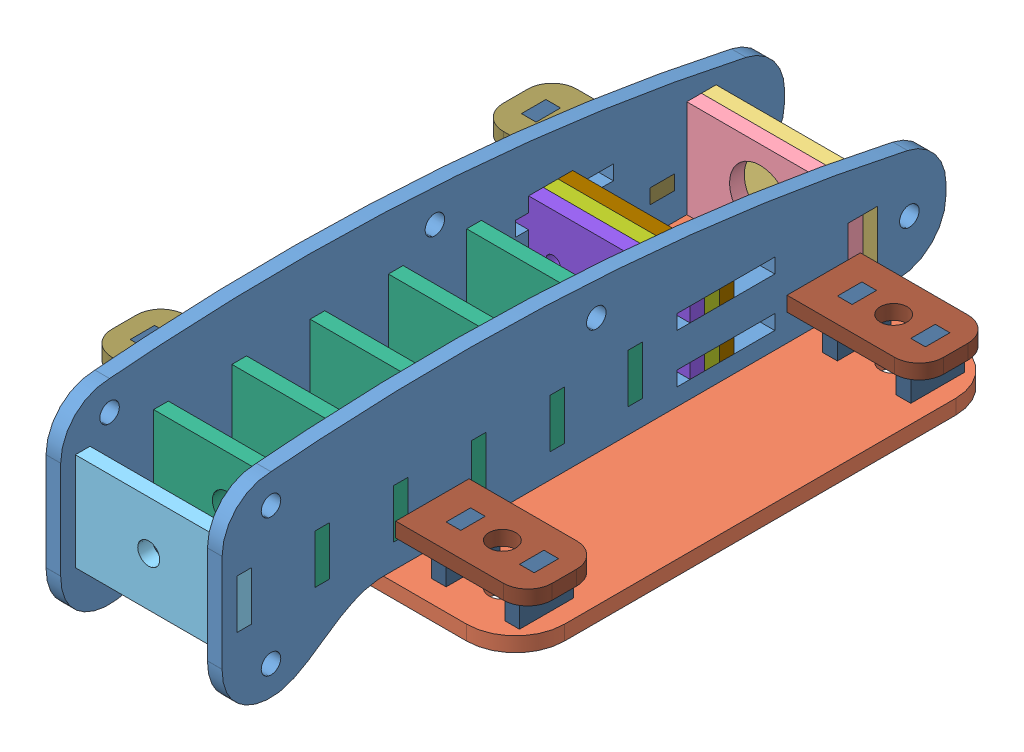
SolidWorks assembly holder_assembly, configuration Default. Lengths in mm.
Overall size (90 45.93 148.02).
26 component instances, 12 part files, 75 mates.
Components (placement in the parent):
- slider_holder-1: slider_holder [Default] at (-5.6502 23.4404 8.9705) x (0 -1 0) z (0 0 1) size (45.93 3 148.02)
- slider_holder-2: slider_holder [Default] at (-38.6502 23.4404 8.9705) x (0 -1 0) z (0 0 1) size (45.93 3 148.02)
- baseplate-1: baseplate [Default] at (-20.6502 20.4404 -26.0295) size (90 3 100)
- top_springstop-2: top_springstop [Default] at (-20.6502 33.4404 -77.0295) x (1 0 0) z (0 -1 0) size (36 3 20)
- top_big_springstop-2: top_big_springstop [Default] at (-20.6502 33.4404 -71.0295) x (-1 0 0) z (0 -1 0) size (36 3 20)
- bottom_stop-2: bottom_stop [Default] at (-20.6502 33.4404 50.9705) x (1 0 0) z (0 -1 0) size (36 3 20)
- pen_bodyholder-1: pen_bodyholder [Default] at (-20.6502 33.4404 -13.0295) x (1 0 0) z (0 -1 0) size (36 3 20)
- pen_bodyholder-2: pen_bodyholder [Default] at (-20.6502 33.4404 2.9705) x (1 0 0) z (0 -1 0) size (36 3 20)
- pen_bodyholder-4: pen_bodyholder [Default] at (-20.6502 33.4404 -29.0295) x (1 0 0) z (0 -1 0) size (36 3 20)
- pen_bodyholder-5: pen_bodyholder [Default] at (-20.6502 33.4404 34.9705) x (1 0 0) z (0 -1 0) size (36 3 20)
- pen_bodyholder-6: pen_bodyholder [Default] at (-20.6502 33.4404 18.9705) x (1 0 0) z (0 -1 0) size (36 3 20)
- spring_slider-1: spring_slider [Default] at (4.2172 29.9404 -44.6987) x (1 0 0) z (0 -1 0) size (36 3 19)
- spring_slider_pen-1: spring_slider_pen [Default] at (4.2172 36.9404 -38.6987) x (1 0 0) z (0 1 0) size (36 3 19)
- spring_slider_spring-1: spring_slider_spring [Default] at (4.2172 29.9404 -47.6987) x (1 0 0) z (0 -1 0) size (36 3 19)
- brace-1: brace [Default] at (-58.9502 36.6605 -67.8741) x (0 1 0) z (0 0 1) size (11.5 3 11)
- brace-2: brace [Default] at (-58.9502 36.6605 12.1259) x (0 1 0) z (0 0 1) size (11.5 3 11)
- brace-3: brace [Default] at (20.6498 36.6605 12.1259) x (0 1 0) z (0 0 1) size (11.5 3 11)
- brace-4: brace [Default] at (20.6498 36.6605 -67.8741) x (0 1 0) z (0 0 1) size (11.5 3 11)
- brace-5: brace [Default] at (5.6498 36.6605 -67.8741) x (0 1 0) z (0 0 1) size (11.5 3 11)
- brace-6: brace [Default] at (-43.9502 36.6605 -67.8741) x (0 1 0) z (0 0 1) size (11.5 3 11)
- brace-7: brace [Default] at (5.6498 36.6605 12.1259) x (0 1 0) z (0 0 1) size (11.5 3 11)
- brace-8: brace [Default] at (-43.9502 36.6605 12.1259) x (0 1 0) z (0 0 1) size (11.5 3 11)
- holder_right-1: holder_right [Default] at (2.5282 28.9404 -68.5295) x (-1 0 0) z (0 0 -1) size (30 3 15)
- holder_right-2: holder_right [Default] at (2.5282 28.9404 11.4705) x (-1 0 0) z (0 0 -1) size (30 3 15)
- holder_left-1: holder_left [Default] at (-43.8287 28.9404 -63.5295) size (30 3 15)
- holder_left-2: holder_left [Default] at (-43.8287 28.9404 16.4705) size (30 3 15)
Mates (geometry in assembly coordinates):
- Coincident16: coincident anti-aligned: plane of slider_holder-1 through (-2.6502 14.2496 42.9836) normal (1 0 0); plane of baseplate-1 through (-2.6502 23.4404 -51.0295) normal (-1 0 0)
- Coincident17: coincident anti-aligned: plane of slider_holder-1 through (-2.6502 20.4404 -71.0295) normal (0 0 -1); plane of baseplate-1 through (-5.6502 23.4404 -71.0295) normal (0 0 1)
- Coincident18: coincident aligned: plane of slider_holder-1 through (-2.6502 20.4404 -61.0295) normal (0 -1 0); plane of baseplate-1 through (-20.6502 20.4404 -26.0295) normal (0 -1 0)
- Coincident19: coincident aligned: plane of slider_holder-2 through (-35.6502 20.4404 -61.0295) normal (0 -1 0); plane of baseplate-1 through (-20.6502 20.4404 -26.0295) normal (0 -1 0)
- Coincident20: coincident anti-aligned: plane of slider_holder-2 through (-35.6502 23.4404 -61.0295) normal (0 0 1); plane of baseplate-1 through (-35.6502 23.4404 -61.0295) normal (0 0 -1)
- Coincident21: coincident anti-aligned: plane of slider_holder-2 through (-38.6502 14.2496 42.9836) normal (-1 0 0); plane of baseplate-1 through (-38.6502 23.4404 -71.0295) normal (1 0 0)
- Coincident25: coincident anti-aligned: plane of top_springstop-2 through (-20.6502 33.4404 -74.0295) normal (0 0 1); plane of top_big_springstop-2 through (-20.6502 33.4404 -74.0295) normal (0 0 -1)
- Coincident26: coincident aligned: plane of top_springstop-2 through (-38.6502 38.4404 -74.0295) normal (-1 0 0); plane of top_big_springstop-2 through (-38.6502 28.4404 -74.0295) normal (-1 0 0)
- Coincident27: coincident aligned: plane of top_springstop-2 through (-5.6502 23.4404 -74.0295) normal (0 -1 0); plane of top_big_springstop-2 through (-35.6502 23.4404 -74.0295) normal (0 -1 0)
- Coincident28: coincident anti-aligned: plane of slider_holder-2 through (-35.6502 28.4404 -71.0295) normal (0 0 -1); plane of top_big_springstop-2 through (-20.6502 33.4404 -71.0295) normal (0 0 1)
- Coincident29: coincident aligned: plane of slider_holder-2 through (-38.6502 14.2496 42.9836) normal (-1 0 0); plane of top_big_springstop-2 through (-38.6502 28.4404 -74.0295) normal (-1 0 0)
- Coincident30: coincident anti-aligned: plane of slider_holder-2 through (-35.6502 38.4404 -77.0295) normal (0 -1 0); plane of top_big_springstop-2 through (-38.6502 38.4404 -74.0295) normal (0 1 0)
- Coincident31: coincident aligned: plane of slider_holder-2 through (-38.6502 14.2496 42.9836) normal (-1 0 0); plane of bottom_stop-2 through (-38.6502 38.4404 53.9705) normal (-1 0 0)
- Coincident32: coincident anti-aligned: plane of slider_holder-2 through (-35.6502 28.4404 50.9705) normal (0 1 0); plane of bottom_stop-2 through (-38.6502 28.4404 53.9705) normal (0 -1 0)
- Coincident33: coincident anti-aligned: plane of slider_holder-2 through (-35.6502 28.4404 53.9705) normal (0 0 -1); plane of bottom_stop-2 through (-20.6502 33.4404 53.9705) normal (0 0 1)
- Coincident35: coincident aligned: plane of slider_holder-1 through (-2.6502 14.2496 42.9836) normal (1 0 0); plane of pen_bodyholder-6 through (-2.6502 28.4404 21.9705) normal (1 0 0)
- Coincident36: coincident aligned: plane of slider_holder-1 through (-2.6502 14.2496 42.9836) normal (1 0 0); plane of pen_bodyholder-5 through (-2.6502 28.4404 37.9705) normal (1 0 0)
- Coincident37: coincident aligned: plane of slider_holder-1 through (-2.6502 14.2496 42.9836) normal (1 0 0); plane of pen_bodyholder-4 through (-2.6502 28.4404 -26.0295) normal (1 0 0)
- Coincident38: coincident aligned: plane of slider_holder-1 through (-2.6502 14.2496 42.9836) normal (1 0 0); plane of pen_bodyholder-1 through (-2.6502 28.4404 -10.0295) normal (1 0 0)
- Coincident39: coincident aligned: plane of slider_holder-1 through (-2.6502 14.2496 42.9836) normal (1 0 0); plane of pen_bodyholder-2 through (-2.6502 28.4404 5.9705) normal (1 0 0)
- Coincident41: coincident anti-aligned: plane of slider_holder-1 through (-2.6502 38.4404 34.9705) normal (0 -1 0); plane of pen_bodyholder-2 through (-2.6502 38.4404 5.9705) normal (0 1 0)
- Coincident43: coincident anti-aligned: plane of slider_holder-1 through (-2.6502 38.4404 34.9705) normal (0 -1 0); plane of pen_bodyholder-1 through (-2.6502 38.4404 -10.0295) normal (0 1 0)
- Coincident44: coincident anti-aligned: plane of slider_holder-1 through (-2.6502 38.4404 34.9705) normal (0 -1 0); plane of pen_bodyholder-4 through (-2.6502 38.4404 -26.0295) normal (0 1 0)
- Coincident46: coincident anti-aligned: plane of slider_holder-1 through (-2.6502 38.4404 34.9705) normal (0 -1 0); plane of pen_bodyholder-5 through (-2.6502 38.4404 37.9705) normal (0 1 0)
- Coincident47: coincident anti-aligned: plane of slider_holder-1 through (-2.6502 38.4404 34.9705) normal (0 -1 0); plane of pen_bodyholder-6 through (-2.6502 38.4404 21.9705) normal (0 1 0)
- Coincident48: coincident anti-aligned: plane of slider_holder-1 through (-2.6502 28.4404 34.9705) normal (0 0 1); plane of pen_bodyholder-5 through (-20.6502 33.4404 34.9705) normal (0 0 -1)
- Coincident49: coincident anti-aligned: plane of slider_holder-1 through (-2.6502 28.4404 21.9705) normal (0 0 -1); plane of pen_bodyholder-6 through (-20.6502 33.4404 21.9705) normal (0 0 1)
- Coincident50: coincident anti-aligned: plane of slider_holder-1 through (-2.6502 28.4404 2.9705) normal (0 0 1); plane of pen_bodyholder-2 through (-20.6502 33.4404 2.9705) normal (0 0 -1)
- Coincident51: coincident anti-aligned: plane of slider_holder-1 through (-2.6502 28.4404 -10.0295) normal (0 0 -1); plane of pen_bodyholder-1 through (-20.6502 33.4404 -10.0295) normal (0 0 1)
- Coincident52: coincident anti-aligned: plane of slider_holder-1 through (-2.6502 28.4404 -29.0295) normal (0 0 1); plane of pen_bodyholder-4 through (-20.6502 33.4404 -29.0295) normal (0 0 -1)
- Coincident55: coincident aligned: plane of slider_holder-2 through (-38.6502 14.2496 42.9836) normal (-1 0 0); plane of spring_slider-1 through (-38.6502 26.9404 -41.6987) normal (-1 0 0)
- Coincident56: coincident anti-aligned: plane of slider_holder-2 through (-35.6502 39.9404 -36.0295) normal (0 -1 0); plane of spring_slider-1 through (-38.6502 39.9404 -41.6987) normal (0 1 0)
- Coincident57: coincident anti-aligned: plane of spring_slider-1 through (4.2172 29.9404 -44.6987) normal (0 0 -1); plane of spring_slider_spring-1 through (4.2172 29.9404 -44.6987) normal (0 0 1)
- Coincident58: coincident aligned: plane of slider_holder-2 through (-38.6502 14.2496 42.9836) normal (-1 0 0); plane of spring_slider_spring-1 through (-38.6502 36.9404 -44.6987) normal (-1 0 0)
- Coincident59: coincident anti-aligned: plane of slider_holder-2 through (-35.6502 39.9404 -36.0295) normal (0 -1 0); plane of spring_slider_spring-1 through (-38.6502 39.9404 -44.6987) normal (0 1 0)
- Coincident60: coincident anti-aligned: plane of spring_slider-1 through (4.2172 29.9404 -41.6987) normal (0 0 1); plane of spring_slider_pen-1 through (4.2172 36.9404 -41.6987) normal (0 0 -1)
- Coincident61: coincident aligned: plane of slider_holder-2 through (-38.6502 14.2496 42.9836) normal (-1 0 0); plane of spring_slider_pen-1 through (-38.6502 39.9404 -41.6987) normal (-1 0 0)
- Coincident62: coincident anti-aligned: plane of slider_holder-2 through (-35.6502 39.9404 -36.0295) normal (0 -1 0); plane of spring_slider_pen-1 through (-35.6502 39.9404 -41.6987) normal (0 1 0)
- Coincident63: coincident aligned: plane of baseplate-1 through (-20.6502 20.4404 -26.0295) normal (0 -1 0); plane of brace-1 through (-61.9502 20.4404 -63.5295) normal (0 -1 0)
- Coincident64: coincident aligned: plane of baseplate-1 through (-20.6502 20.4404 -26.0295) normal (0 -1 0); plane of brace-4 through (17.6498 20.4404 -63.5295) normal (0 -1 0)
- Coincident65: coincident aligned: plane of baseplate-1 through (-20.6502 20.4404 -26.0295) normal (0 -1 0); plane of brace-2 through (-61.9502 20.4404 16.4705) normal (0 -1 0)
- Coincident66: coincident aligned: plane of baseplate-1 through (-20.6502 20.4404 -26.0295) normal (0 -1 0); plane of brace-3 through (17.6498 20.4404 16.4705) normal (0 -1 0)
- Coincident67: coincident aligned: plane of brace-1 through (-61.9502 31.9404 -63.5295) normal (0 0 1); plane of brace-4 through (17.6498 31.9404 -63.5295) normal (0 0 1)
- Coincident69: coincident anti-aligned: plane of brace-1 through (-61.9502 31.9404 -63.5295) normal (0 0 1); plane of baseplate-1 through (-58.9502 23.4404 -63.5295) normal (0 0 -1)
- Coincident70: coincident anti-aligned: plane of baseplate-1 through (-61.9502 23.4404 -68.5295) normal (1 0 0); plane of brace-1 through (-61.9502 36.6605 -67.8741) normal (-1 0 0)
- Coincident71: coincident anti-aligned: plane of baseplate-1 through (17.6498 23.4404 -68.5295) normal (1 0 0); plane of brace-4 through (17.6498 36.6605 -67.8741) normal (-1 0 0)
- Coincident72: coincident anti-aligned: plane of baseplate-1 through (-61.9502 23.4404 16.4705) normal (1 0 0); plane of brace-2 through (-61.9502 36.6605 12.1259) normal (-1 0 0)
- Coincident73: coincident anti-aligned: plane of baseplate-1 through (-58.9502 23.4404 11.4705) normal (0 0 1); plane of brace-2 through (-61.9502 28.9404 11.4705) normal (0 0 -1)
- Coincident74: coincident anti-aligned: plane of baseplate-1 through (20.6498 23.4404 16.4705) normal (-1 0 0); plane of brace-3 through (20.6498 36.6605 12.1259) normal (1 0 0)
- Coincident75: coincident anti-aligned: plane of baseplate-1 through (17.6498 23.4404 11.4705) normal (0 0 1); plane of brace-3 through (17.6498 28.9404 11.4705) normal (0 0 -1)
- Coincident78: coincident aligned: plane of baseplate-1 through (-20.6502 20.4404 -26.0295) normal (0 -1 0); plane of brace-8 through (-46.9502 20.4404 16.4705) normal (0 -1 0)
- Coincident79: coincident aligned: plane of baseplate-1 through (-20.6502 20.4404 -26.0295) normal (0 -1 0); plane of brace-7 through (2.6498 20.4404 16.4705) normal (0 -1 0)
- Coincident80: coincident aligned: plane of baseplate-1 through (-20.6502 20.4404 -26.0295) normal (0 -1 0); plane of brace-6 through (-46.9502 20.4404 -63.5295) normal (0 -1 0)
- Coincident81: coincident aligned: plane of baseplate-1 through (-20.6502 20.4404 -26.0295) normal (0 -1 0); plane of brace-5 through (2.6498 20.4404 -63.5295) normal (0 -1 0)
- Coincident82: coincident aligned: plane of brace-8 through (-46.9502 36.6605 12.1259) normal (-1 0 0); plane of brace-6 through (-46.9502 36.6605 -67.8741) normal (-1 0 0)
- Coincident87: coincident aligned: plane of brace-6 through (-46.9502 36.6605 -67.8741) normal (-1 0 0); plane of brace-8 through (-46.9502 36.6605 12.1259) normal (-1 0 0)
- Coincident88: coincident anti-aligned: plane of brace-6 through (-46.9502 36.6605 -67.8741) normal (-1 0 0); plane of baseplate-1 through (-46.9502 23.4404 -68.5295) normal (1 0 0)
- Coincident89: coincident anti-aligned: plane of baseplate-1 through (-46.9502 23.4404 -68.5295) normal (0 0 1); plane of brace-6 through (-46.9502 28.9404 -68.5295) normal (0 0 -1)
- Coincident90: coincident anti-aligned: plane of baseplate-1 through (-46.9502 23.4404 16.4705) normal (0 0 -1); plane of brace-8 through (-46.9502 31.9404 16.4705) normal (0 0 1)
- Coincident91: coincident anti-aligned: plane of baseplate-1 through (2.6498 23.4404 -68.5295) normal (1 0 0); plane of brace-5 through (2.6498 36.6605 -67.8741) normal (-1 0 0)
- Coincident92: coincident anti-aligned: plane of baseplate-1 through (5.6498 23.4404 -63.5295) normal (0 0 -1); plane of brace-5 through (2.6498 31.9404 -63.5295) normal (0 0 1)
- Coincident93: coincident anti-aligned: plane of baseplate-1 through (5.6498 23.4404 16.4705) normal (-1 0 0); plane of brace-7 through (5.6498 36.6605 12.1259) normal (1 0 0)
- Coincident94: coincident anti-aligned: plane of baseplate-1 through (5.6498 23.4404 11.4705) normal (0 0 1); plane of brace-7 through (2.6498 28.9404 11.4705) normal (0 0 -1)
- Coincident95: coincident aligned: plane of holder_left-2 through (-43.8287 31.9404 16.4705) normal (0 1 0); plane of holder_left-1 through (-43.8287 31.9404 -63.5295) normal (0 1 0)
- Coincident96: coincident aligned: plane of holder_left-2 through (-43.8287 31.9404 16.4705) normal (0 1 0); plane of brace-8 through (-46.9502 31.9404 11.4705) normal (0 1 0)
- Coincident97: coincident aligned: plane of holder_left-2 through (-35.6502 31.9404 11.4705) normal (1 0 0); plane of holder_left-1 through (-35.6502 31.9404 -68.5295) normal (1 0 0)
- Coincident98: coincident aligned: plane of holder_left-2 through (-35.6502 31.9404 11.4705) normal (1 0 0); plane of slider_holder-2 through (-35.6502 14.2496 42.9836) normal (1 0 0)
- Coincident99: coincident anti-aligned: plane of brace-2 through (-61.9502 28.9404 11.4705) normal (0 0 -1); plane of holder_left-2 through (-58.9502 31.9404 11.4705) normal (0 0 1)
- Coincident100: coincident anti-aligned: plane of brace-1 through (-61.9502 28.9404 -68.5295) normal (0 0 -1); plane of holder_left-1 through (-58.9502 31.9404 -68.5295) normal (0 0 1)
- Coincident101: coincident aligned: plane of holder_right-2 through (-5.6502 31.9404 16.4705) normal (-1 0 0); plane of holder_right-1 through (-5.6502 31.9404 -63.5295) normal (-1 0 0)
- Coincident102: coincident aligned: plane of holder_right-2 through (-5.6502 31.9404 16.4705) normal (-1 0 0); plane of slider_holder-1 through (-5.6502 14.2496 42.9836) normal (-1 0 0)
- Coincident103: coincident aligned: plane of holder_right-2 through (2.5282 31.9404 11.4705) normal (0 1 0); plane of holder_right-1 through (2.5282 31.9404 -68.5295) normal (0 1 0)
- Coincident104: coincident aligned: plane of holder_right-2 through (2.5282 31.9404 11.4705) normal (0 1 0); plane of brace-4 through (17.6498 31.9404 -68.5295) normal (0 1 0)
- Coincident105: coincident anti-aligned: plane of brace-7 through (2.6498 28.9404 11.4705) normal (0 0 -1); plane of holder_right-2 through (5.6498 31.9404 11.4705) normal (0 0 1)
- Coincident106: coincident anti-aligned: plane of brace-5 through (2.6498 31.9404 -63.5295) normal (0 0 1); plane of holder_right-1 through (5.6498 31.9404 -63.5295) normal (0 0 -1)
